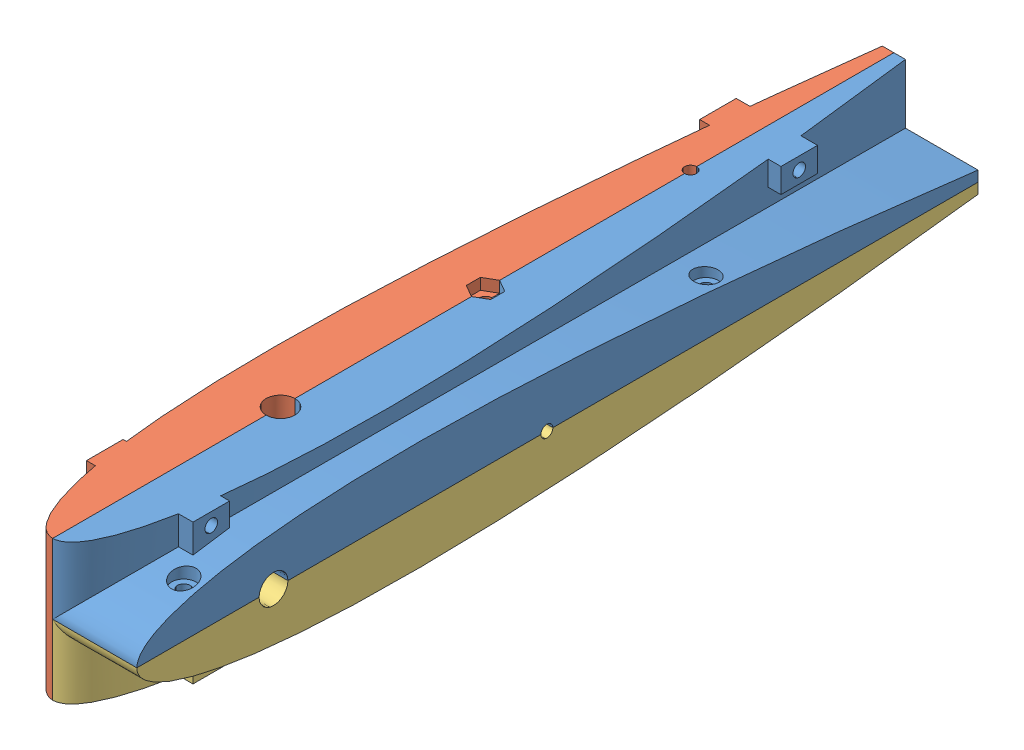
SolidWorks assembly tail_clampAssem_v1b, configuration Default. Lengths in mm.
Overall size (62.95 74.42 301.96).
4 component instances, 4 part files, 23 mates.
Components (placement in the parent):
- tail_clampJointInside_v1.3-1: tail_clampJointInside_v1.3 [Default] at (-31.5 25 0) x (0 0 -1) z (0 -1 0) size (301.96 57.54 57.66)
- tail_clampJointOutside_v1.3-1: tail_clampJointOutside_v1.3 [Default] at (-31.5 25 0) x (0 0 -1) z (0 -1 0) size (300 29.21 50.36)
- tail_clampRevolve_v1.3-1: tail_clampRevolve_v1.3 [Default] at (-31.5 25 0) x (0 0 -1) z (0 1 0) (suppressed, hidden)
- Mirrortail_clampJointInside_v1.3-3: Mirrortail_clampJointInside_v1.3 [Default] at (-31.5 -25 0) x (0 0 -1) z (0 -1 0) size (301.96 57.54 57.66)
Mates (geometry in assembly coordinates):
- Coincident9: coincident aligned: plane of ? through (0 0 0) normal (0 1 0); plane of assembly through (0 0 0) normal (0 1 0)
- Coincident10: coincident anti-aligned: plane of ? through (0 0 0) normal (0 0 -1); plane of assembly through (0 0 0) normal (0 0 1)
- Concentric6: concentric aligned: cylinder of ? through (125 0 -146.25) axis (1 0 0) radius 2; cylinder of ? through (145 0 -146.25) axis (1 0 0) radius 2.5
- Concentric7: concentric aligned: cylinder of ? through (-127.0234 0 -48.75) axis (1 0 0) radius 5; cylinder of ? through (145 0 -48.75) axis (1 0 0) radius 5.5
- Coincident13: coincident anti-aligned: plane of ? through (145 0 0) normal (1 0 0); plane of ? through (145 0 0) normal (-1 0 0)
- Coincident14: coincident anti-aligned: plane of ? through (-145 0 0) normal (-1 0 0); plane of ? through (-145 0 0) normal (1 0 0)
- Concentric9: concentric anti-aligned: cylinder of ? through (-125 0 -146.25) axis (-1 0 0) radius 2; cylinder of ? through (-146.5 0 -146.25) axis (1 0 0) radius 2.5
- Coincident15: coincident anti-aligned: plane of ? through (145 -19.511 -295) normal (0 0 -1); plane of ? through (-236.376 -4.5311 -295) normal (0 0 1)
- Coincident16: coincident aligned: plane of ? through (-526.376 0 -325) normal (0 1 0); plane of assembly through (0 0 0) normal (0 1 0)
- Coincident17: coincident anti-aligned: plane of ? through (-1.5 0 0) normal (-1 0 0); plane of tail_clampJointInside_v1.3-1 through (-1.5 17.3476 -160.2188) normal (1 0 0)
- Concentric13: concentric anti-aligned: cylinder of ? through (-125 0 -146.25) axis (-1 0 0) radius 2; cylinder of tail_clampJointInside_v1.3-1 through (-161.5 0 -146.25) axis (1 0 0) radius 2.15
- Coincident19: coincident anti-aligned: plane of tail_clampJointInside_v1.3-1 through (-31.5 0 -325) normal (-1 0 0); plane of tail_clampJointOutside_v1.3-1 through (-31.5 -25 -325) normal (1 0 0)
- Coincident20: coincident aligned: plane of tail_clampJointInside_v1.3-1 through (-13.9537 25 -160.1975) normal (0 1 0); plane of tail_clampJointOutside_v1.3-1 through (-49.0463 25 -160.1975) normal (0 1 0)
- Coincident21: coincident aligned: plane of tail_clampJointInside_v1.3-1 through (-31.5 25 0) normal (0 0 -1); plane of tail_clampJointOutside_v1.3-1 through (-31.5 25 0) normal (0 0 -1)
- Coincident23: coincident aligned: plane of ? through (0 0 0) normal (1 0 0); plane of assembly through (0 0 0) normal (1 0 0)
- Coincident24: coincident anti-aligned: plane of tail_clampJointInside_v1.3-1 through (-13.9537 25 -160.1975) normal (0 1 0); plane of tail_clampRevolve_v1.3-1 through (-31.5 25 0) normal (0 -1 0)
- Concentric14: concentric aligned: cylinder of tail_clampJointInside_v1.3-1 through (-31.5 27.9166 -81.25) axis (0 -1 0) radius 5.15; cylinder of tail_clampRevolve_v1.3-1 through (-31.5 34 -81.25) axis (0 -1 0) radius 5.15
- Concentric15: concentric aligned: cylinder of tail_clampJointOutside_v1.3-1 through (-31.5 25 -154.375) axis (0 -1 0) radius 2.25; cylinder of tail_clampRevolve_v1.3-1 through (-31.5 34 -154.375) axis (0 -1 0) radius 2.25
- Concentric16: concentric aligned: cylinder of ? through (-1.5 0 -48.75) axis (1 0 0) radius 5.5; cylinder of tail_clampJointInside_v1.3-1 through (-40.0201 0 -48.75) axis (1 0 0) radius 5.15
- Concentric17: concentric aligned: cylinder of ? through (-1.5 0 -146.25) axis (1 0 0) radius 2.5; cylinder of tail_clampJointInside_v1.3-1 through (-16.5 0 -146.25) axis (1 0 0) radius 2.15
- Coincident25: coincident aligned: plane of ? through (0 0 0) normal (1 0 0); plane of assembly through (0 0 0) normal (1 0 0)
- Coincident26: coincident aligned: plane of ? through (-1.5 0 0) normal (0 1 0); plane of assembly through (0 0 0) normal (0 1 0)
- Coincident27: coincident anti-aligned: plane of ? through (-1.5 0 0) normal (0 0 -1); plane of assembly through (0 0 0) normal (0 0 1)
